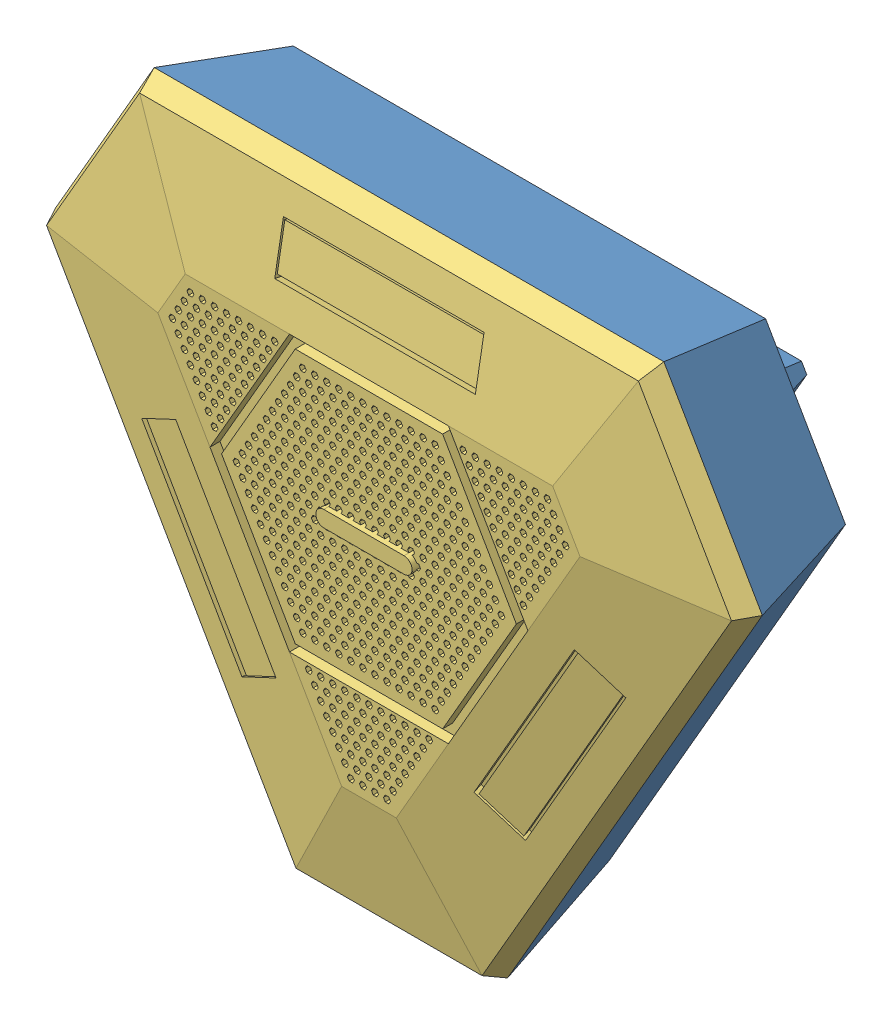
SolidWorks assembly END, configuration Default. Lengths in mm.
Overall size (352.18 305 152.5).
8 component instances, 3 part files, 15 mates.
Components (placement in the parent):
- END-Lumenizer 300 Casing-1: END-Lumenizer 300 Casing [Default] at origin size (352.18 305 122)
- B18.6.7M - M5 x 0.8 x 20 Indented HFMS --20S-1: B18.6.7M - M5 x 0.8 x 20 Indented HFMS --20S [B18.6.7M - M5 x 0.8 x 20 Indented HFMS --20S] at (-25 0 -104.6) x (0 0 -1) z (1 0 0) size (25.4 10.6 10.6)
- B18.6.7M - M5 x 0.8 x 20 Indented HFMS --20S-2: B18.6.7M - M5 x 0.8 x 20 Indented HFMS --20S [B18.6.7M - M5 x 0.8 x 20 Indented HFMS --20S] at (-12.5 21.6506 -104.6) x (0 0 -1) z (1 0 0) size (25.4 10.6 10.6)
- B18.6.7M - M5 x 0.8 x 20 Indented HFMS --20S-3: B18.6.7M - M5 x 0.8 x 20 Indented HFMS --20S [B18.6.7M - M5 x 0.8 x 20 Indented HFMS --20S] at (12.5 21.6506 -104.6) x (0 0 -1) z (1 0 0) size (25.4 10.6 10.6)
- B18.6.7M - M5 x 0.8 x 20 Indented HFMS --20S-4: B18.6.7M - M5 x 0.8 x 20 Indented HFMS --20S [B18.6.7M - M5 x 0.8 x 20 Indented HFMS --20S] at (-12.5 -21.6506 -104.6) x (0 0 -1) z (1 0 0) size (25.4 10.6 10.6)
- B18.6.7M - M5 x 0.8 x 20 Indented HFMS --20S-5: B18.6.7M - M5 x 0.8 x 20 Indented HFMS --20S [B18.6.7M - M5 x 0.8 x 20 Indented HFMS --20S] at (12.5 -21.6506 -104.6) x (0 0 -1) z (1 0 0) size (25.4 10.6 10.6)
- B18.6.7M - M5 x 0.8 x 20 Indented HFMS --20S-6: B18.6.7M - M5 x 0.8 x 20 Indented HFMS --20S [B18.6.7M - M5 x 0.8 x 20 Indented HFMS --20S] at (25 0 -104.6) x (0 0 -1) z (1 0 0) size (25.4 10.6 10.6)
- END-Lumenizer 300 Face-1: END-Lumenizer 300 Face [Default] at origin size (352.18 305 22.5)
Mates (geometry in assembly coordinates):
- Concentric11: concentric: cylinder of ? through (-25 0 0.001) axis (0 0 -1) radius 2.5; cylinder of B18.6.7M - M5 x 0.8 x 20 Indented HFMS --20S-1 through (-25 0 -79.2) axis (0 0 1) radius 2.5
- Coincident11: coincident: plane of ? through (0 0 -110) normal (0 0 1); plane of B18.6.7M - M5 x 0.8 x 20 Indented HFMS --20S-1 through (-25 2.5 -110) normal (0 0 -1)
- Concentric21: concentric: cylinder of ? through (-12.5 21.6506 0.001) axis (0 0 -1) radius 2.5; cylinder of B18.6.7M - M5 x 0.8 x 20 Indented HFMS --20S-2 through (-12.5 21.6506 -79.2) axis (0 0 1) radius 2.5
- Coincident21: coincident: plane of ? through (0 0 -110) normal (0 0 1); plane of B18.6.7M - M5 x 0.8 x 20 Indented HFMS --20S-2 through (-12.5 24.1506 -110) normal (0 0 -1)
- Concentric31: concentric: cylinder of ? through (12.5 21.6506 0.001) axis (0 0 -1) radius 2.5; cylinder of B18.6.7M - M5 x 0.8 x 20 Indented HFMS --20S-3 through (12.5 21.6506 -79.2) axis (0 0 1) radius 2.5
- Coincident31: coincident: plane of ? through (0 0 -110) normal (0 0 1); plane of B18.6.7M - M5 x 0.8 x 20 Indented HFMS --20S-3 through (12.5 24.1506 -110) normal (0 0 -1)
- Concentric41: concentric: cylinder of ? through (-12.5 -21.6506 0.001) axis (0 0 -1) radius 2.5; cylinder of B18.6.7M - M5 x 0.8 x 20 Indented HFMS --20S-4 through (-12.5 -21.6506 -79.2) axis (0 0 1) radius 2.5
- Coincident41: coincident: plane of ? through (0 0 -110) normal (0 0 1); plane of B18.6.7M - M5 x 0.8 x 20 Indented HFMS --20S-4 through (-12.5 -19.1506 -110) normal (0 0 -1)
- Concentric51: concentric: cylinder of ? through (12.5 -21.6506 0.001) axis (0 0 -1) radius 2.5; cylinder of B18.6.7M - M5 x 0.8 x 20 Indented HFMS --20S-5 through (12.5 -21.6506 -79.2) axis (0 0 1) radius 2.5
- Coincident51: coincident: plane of ? through (0 0 -110) normal (0 0 1); plane of B18.6.7M - M5 x 0.8 x 20 Indented HFMS --20S-5 through (12.5 -19.1506 -110) normal (0 0 -1)
- Concentric61: concentric: cylinder of ? through (25 0 0.001) axis (0 0 -1) radius 2.5; cylinder of B18.6.7M - M5 x 0.8 x 20 Indented HFMS --20S-6 through (25 0 -79.2) axis (0 0 1) radius 2.5
- Coincident61: coincident: plane of ? through (0 0 -110) normal (0 0 1); plane of B18.6.7M - M5 x 0.8 x 20 Indented HFMS --20S-6 through (25 2.5 -110) normal (0 0 -1)
- Coincident7: coincident: line of ? through (254.0341 127.0171 130) axis (0 -1 0); line of ? through (254.0341 127.0171 130) axis (0 -1 0)
- Coincident9: coincident: plane of ? through (0 0 0) normal (0 0 1); plane of ? through (0 0 0) normal (0 0 -1)
- Coincident10: coincident: line of ? through (254.0341 49.0748 -175) axis (0 0.5 0.866025); line of ? through (254.0341 49.0748 -175) axis (0 0.5 0.866025)
